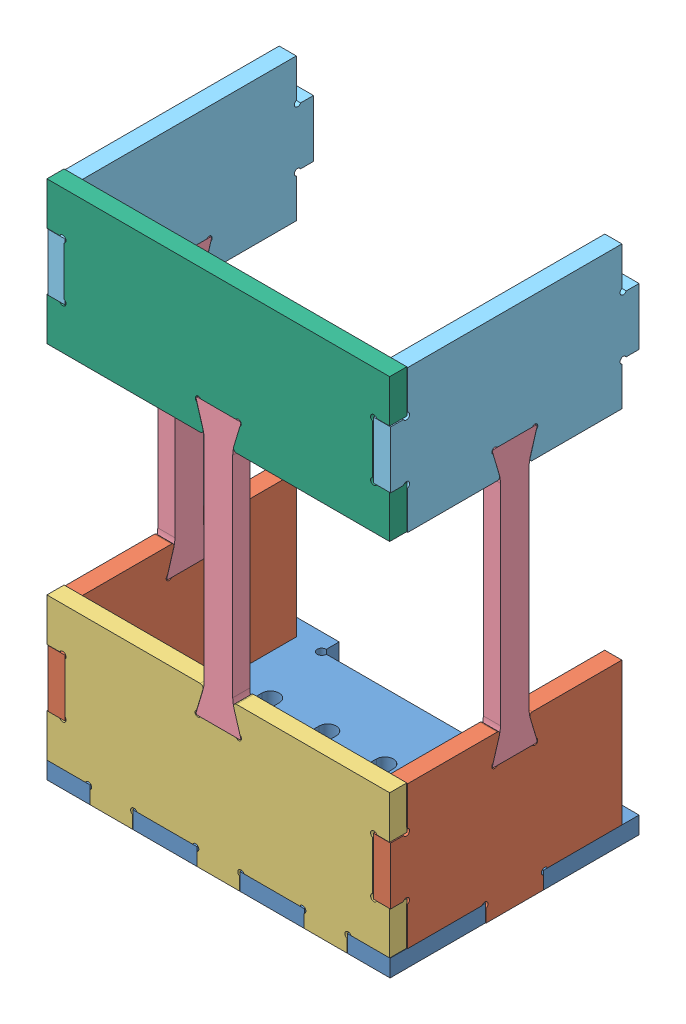
SolidWorks assembly Porta_Paraguas, configuration Predeterminado. Lengths in mm.
Overall size (240.64 364.5 174.05).
10 component instances, 6 part files, 27 mates.
Components (placement in the parent):
- P_base-1: P_base [Predeterminado] at (-123.7142 -25.5418 322.3166) size (240.64 12 174)
- P_base_lateral-1: P_base_lateral [Predeterminado] at (-123.0754 86.4582 310.3666) x (0 0 1) z (1 0 0) size (162 112 12)
- P_base_tapa-1: P_base_tapa [Predeterminado] at (-123.7142 86.6263 322.3166) x (1 0 0) z (0 1 0) size (240 12 112.17)
- P_largueros-1: P_largueros [Predeterminado] at (104.9246 239.0936 235.3666) x (0 0 -1) z (1 0 0) size (31.31 192.94 12)
- P_base_lateral-2: P_base_lateral [Predeterminado] at (104.9246 86.4582 310.3666) x (0 0 1) z (1 0 0) size (162 112 12)
- P_largueros-2: P_largueros [Predeterminado] at (-3.6254 239.2617 310.3166) size (31.31 192.94 12)
- P_largueros-3: P_largueros [Predeterminado] at (-111.0754 86.1582 235.3166) x (0 0 -1) z (-1 0 0) size (31.31 192.94 12)
- P_lateral-1: P_lateral [Predeterminado] at (104.9246 238.7936 160.3166) x (0 0 -1) z (1 0 0) size (174 100 12)
- P_tapa-1: P_tapa [Predeterminado] at (-123.7142 238.9617 310.3166) x (1 0 0) z (0 -1 0) size (240 12 100)
- P_lateral-2: P_lateral [Predeterminado] at (-123.0754 238.7936 160.3166) x (0 0 -1) z (1 0 0) size (174 100 12)
Mates (geometry in assembly coordinates):
- Coincidente34: coincident anti-aligned: plane of P_base-1 through (104.9246 -13.5418 218.2666) normal (1 0 0); plane of P_base_lateral-2 through (104.9246 57.4015 311.3099) normal (-1 0 0)
- Coincidente35: coincident anti-aligned: plane of P_base-1 through (116.5858 -13.5418 255.3666) normal (0 0 -1); plane of P_base_lateral-2 through (116.9246 -25.5418 255.3666) normal (0 0 1)
- Coincidente36: coincident anti-aligned: plane of P_base-1 through (-92.8073 -13.5418 311.2235) normal (0 1 0); plane of P_base_lateral-2 through (116.9246 -13.5418 212.3666) normal (0 -1 0)
- Coincidente40: coincident aligned: plane of P_base-1 through (-92.8073 -25.5418 311.2235) normal (0 -1 0); plane of P_base_lateral-1 through (-111.0754 -25.5418 215.3666) normal (0 -1 0)
- Coincidente41: coincident anti-aligned: plane of P_base-1 through (-114.0754 -13.5418 255.3666) normal (0 0 -1); plane of P_base_lateral-1 through (-111.0754 -25.5418 255.3666) normal (0 0 1)
- Coincidente42: coincident anti-aligned: plane of P_base-1 through (-111.0754 -13.5418 218.2666) normal (-1 0 0); plane of P_base_lateral-1 through (-111.0754 57.4015 311.3099) normal (1 0 0)
- Coincidente43: coincident aligned: plane of P_base-1 through (-92.8073 -25.5418 311.2235) normal (0 -1 0); plane of P_base_tapa-1 through (-18.7142 -25.5418 310.3166) normal (0 -1 0)
- Coincidente44: coincident anti-aligned: plane of P_base-1 through (-66.6142 -13.5418 310.3166) normal (0 0 1); plane of P_base_tapa-1 through (-16.4166 84.5633 310.3166) normal (0 0 -1)
- Coincidente45: coincident aligned: plane of P_base-1 through (-123.7142 -13.5418 255.3666) normal (-1 0 0); plane of P_base_tapa-1 through (-123.7142 -13.5418 310.3166) normal (-1 0 0)
- Coincidente46: coincident anti-aligned: plane of P_largueros-1 through (116.9246 66.1582 250.0226) normal (0 -1 0); plane of P_base_lateral-2 through (116.9246 66.1582 223.1166) normal (0 1 0)
- Coincidente47: coincident aligned: plane of P_largueros-1 through (116.9246 236.1582 205.3666) normal (1 0 0); plane of P_base_lateral-2 through (116.9246 57.4015 311.3099) normal (1 0 0)
- Distancia1: distance = 65 mm aligned: plane of P_largueros-1 through (116.9246 236.1582 225.3666) normal (0 0 -1); plane of P_base_lateral-2 through (116.9246 86.4582 160.3666) normal (0 0 -1)
- Coincidente49: coincident anti-aligned: plane of P_base_lateral-1 through (-111.0754 66.1582 223.1166) normal (0 1 0); plane of P_largueros-3 through (-123.0754 66.1582 249.9726) normal (0 -1 0)
- Coincidente50: coincident aligned: plane of P_base_lateral-1 through (-123.0754 57.4015 311.3099) normal (-1 0 0); plane of P_largueros-3 through (-123.0754 89.0936 205.3166) normal (-1 0 0)
- Coincidente52: coincident anti-aligned: plane of P_base_tapa-1 through (8.9358 66.3263 310.3166) normal (0 1 0); plane of P_largueros-2 through (-18.2614 66.3263 322.3166) normal (0 -1 0)
- Coincidente53: coincident aligned: plane of P_base_tapa-1 through (-16.4166 84.5633 322.3166) normal (0 0 1); plane of P_largueros-2 through (26.3946 236.3263 322.3166) normal (0 0 1)
- Distancia3: distance = 110.55 mm aligned: plane of P_largueros-2 through (6.3746 236.3263 322.3166) normal (1 0 0); plane of P_base_lateral-2 through (116.9246 57.4015 311.3099) normal (1 0 0)
- Coincidente57: coincident aligned: plane of P_largueros-1 through (116.9246 236.1582 205.3666) normal (1 0 0); plane of P_lateral-1 through (116.9246 267.8503 159.3733) normal (1 0 0)
- Coincidente64: coincident aligned: plane of P_largueros-2 through (26.3946 236.3263 322.3166) normal (0 0 1); plane of P_tapa-1 through (-16.4166 241.0247 322.3166) normal (0 0 1)
- Coincidente66: coincident aligned: plane of P_base_tapa-1 through (116.2858 86.6263 310.3166) normal (1 0 0); plane of P_tapa-1 through (116.2858 238.9617 322.3166) normal (1 0 0)
- Coincidente68: coincident aligned: plane of P_largueros-3 through (-123.0754 89.0936 205.3166) normal (-1 0 0); plane of P_lateral-2 through (-123.0754 267.8503 159.3733) normal (-1 0 0)
- Coincidente70: coincident aligned: plane of P_lateral-1 through (116.9246 268.7936 322.3166) normal (0 0 1); plane of P_tapa-1 through (-16.4166 241.0247 322.3166) normal (0 0 1)
- Coincidente71: coincident anti-aligned: plane of P_largueros-1 through (116.9246 259.0936 250.0226) normal (0 1 0); plane of P_lateral-1 through (116.9246 259.0936 235.3166) normal (0 -1 0)
- Coincidente72: coincident aligned: plane of P_largueros-3 through (-123.0754 89.0936 205.3166) normal (-1 0 0); plane of P_lateral-2 through (-123.0754 267.8503 159.3733) normal (-1 0 0)
- Coincidente73: coincident aligned: plane of P_tapa-1 through (-16.4166 241.0247 322.3166) normal (0 0 1); plane of P_lateral-2 through (-111.0754 268.7936 322.3166) normal (0 0 1)
- Coincidente74: coincident anti-aligned: plane of P_largueros-3 through (-123.0754 259.0936 249.9726) normal (0 1 0); plane of P_lateral-2 through (-111.0754 259.0936 235.3166) normal (0 -1 0)
- Distancia4: distance = 77 mm aligned: plane of P_base_tapa-1 through (-16.4166 84.5633 322.3166) normal (0 0 1); plane of P_largueros-3 through (-123.0754 89.0936 245.3166) normal (0 0 1)
